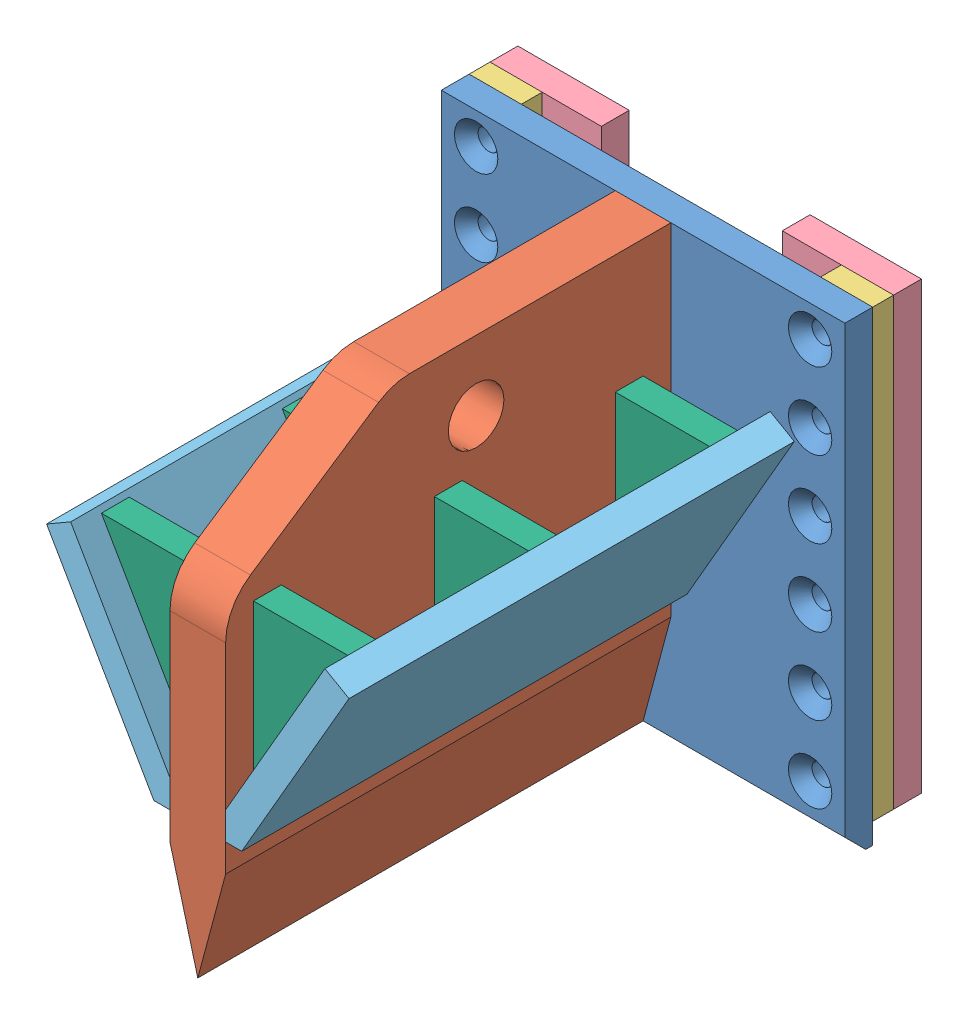
SolidWorks assembly Wedge Mk2 Assb, configuration Default. Lengths in mm.
Overall size (184.15 212.72 238.12).
14 component instances, 6 part files, 48 mates.
Components (placement in the parent):
- Wedge Mk2 Base-1: Wedge Mk2 Base [Default] at (37.464 81.8685 125.6409) size (184.15 212.72 12.7)
- Wedge Mk2-1: Wedge Mk2 [Default] at (37.464 -14.969 233.5909) size (25.4 203.2 203.2)
- Wedge Mk2 Spacer-1: Wedge Mk2 Spacer [Default] at (-42.7048 86.631 114.5284) x (-1 0 0) z (0 0 1) size (23.81 203.2 9.53)
- Wedge Mk2 Spacer-2: Wedge Mk2 Spacer [Default] at (117.6327 86.631 114.5284) size (23.81 203.2 9.53)
- Wedge Mk2 Guide-1: Wedge Mk2 Guide [Default] at (104.139 86.631 103.4159) x (-1 0 0) z (0 0 1) size (50.8 203.2 12.7)
- Wedge Mk2 Guide-2: Wedge Mk2 Guide [Default] at (-29.211 86.631 103.4159) size (50.8 203.2 12.7)
- Wedge Mk2 Spreader-1: Wedge Mk2 Spreader [Default] at (75.564 89.1221 233.5909) x (0.866025 -0.5 0) z (0 0 1) size (12.7 101.6 203.2)
- Wedge Mk2 Spreader-2: Wedge Mk2 Spreader [Default] at (-0.636 89.1221 233.5909) x (-0.866025 -0.5 0) z (0 0 -1) size (12.7 101.6 203.2)
- Wedge Mk2 Spreader Support-1: Wedge Mk2 Spreader Support [Default] at (24.764 134.028 151.0409) x (-1 0 0) z (0 0 -1) size (43.99 76.2 12.7)
- Wedge Mk2 Spreader Support-2: Wedge Mk2 Spreader Support [Default] at (24.764 134.028 233.5909) x (-1 0 0) z (0 0 -1) size (43.99 76.2 12.7)
- Wedge Mk2 Spreader Support-3: Wedge Mk2 Spreader Support [Default] at (24.764 134.028 316.1409) x (-1 0 0) z (0 0 -1) size (43.99 76.2 12.7)
- Wedge Mk2 Spreader Support-4: Wedge Mk2 Spreader Support [Default] at (50.164 134.028 316.1409) size (43.99 76.2 12.7)
- Wedge Mk2 Spreader Support-5: Wedge Mk2 Spreader Support [Default] at (50.164 134.028 233.5909) size (43.99 76.2 12.7)
- Wedge Mk2 Spreader Support-6: Wedge Mk2 Spreader Support [Default] at (50.164 134.028 151.0409) size (43.99 76.2 12.7)
Mates (geometry in assembly coordinates):
- Coincident3: coincident aligned: line of Wedge Mk2 Base-1 through (37.464 188.231 131.9909) axis (0 -1 0); line of Wedge Mk2-1 through (37.464 188.231 131.9909) axis (0 -1 0)
- Coincident4: coincident aligned: line of Wedge Mk2 Base-1 through (129.539 188.231 131.9909) axis (-1 0 0); line of Wedge Mk2-1 through (50.164 188.231 131.9909) axis (-1 0 0)
- Concentric1: concentric aligned: cylinder of Wedge Mk2 Base-1 through (113.664 173.9435 131.9909) axis (0 0 1) radius 4.9022; cylinder of Wedge Mk2 Spacer-2 through (113.664 173.9435 119.2909) axis (0 0 1) radius 4.7625
- Concentric2: concentric aligned: cylinder of Wedge Mk2 Base-1 through (113.664 139.0185 131.9909) axis (0 0 1) radius 4.9022; cylinder of Wedge Mk2 Spacer-2 through (113.664 139.0185 119.2909) axis (0 0 1) radius 4.7625
- Concentric3: concentric aligned: cylinder of Wedge Mk2 Base-1 through (113.664 104.0935 131.9909) axis (0 0 1) radius 4.9022; cylinder of Wedge Mk2 Spacer-2 through (113.664 104.0935 119.2909) axis (0 0 1) radius 4.7625
- Concentric4: concentric aligned: cylinder of Wedge Mk2 Base-1 through (113.664 69.1685 131.9909) axis (0 0 1) radius 4.9022; cylinder of Wedge Mk2 Spacer-2 through (113.664 69.1685 119.2909) axis (0 0 1) radius 4.7625
- Concentric5: concentric aligned: cylinder of Wedge Mk2 Base-1 through (113.664 34.2435 131.9909) axis (0 0 1) radius 4.9022; cylinder of Wedge Mk2 Spacer-2 through (113.664 34.2435 119.2909) axis (0 0 1) radius 4.7625
- Concentric6: concentric aligned: cylinder of Wedge Mk2 Base-1 through (113.664 -0.6815 131.9909) axis (0 0 1) radius 4.9022; cylinder of Wedge Mk2 Spacer-2 through (113.664 -0.6815 119.2909) axis (0 0 1) radius 4.7625
- Coincident17: coincident anti-aligned: plane of Wedge Mk2 Base-1 through (37.464 81.8685 119.2909) normal (0 0 -1); plane of Wedge Mk2 Spacer-2 through (117.6327 86.631 119.2909) normal (0 0 1)
- Concentric7: concentric aligned: cylinder of Wedge Mk2 Base-1 through (-38.736 173.9435 131.9909) axis (0 0 1) radius 4.9022; cylinder of Wedge Mk2 Spacer-1 through (-38.736 173.9435 119.2909) axis (0 0 1) radius 4.7625
- Concentric8: concentric aligned: cylinder of Wedge Mk2 Base-1 through (-38.736 139.0185 131.9909) axis (0 0 1) radius 4.9022; cylinder of Wedge Mk2 Spacer-1 through (-38.736 139.0185 119.2909) axis (0 0 1) radius 4.7625
- Concentric9: concentric aligned: cylinder of Wedge Mk2 Base-1 through (-38.736 104.0935 131.9909) axis (0 0 1) radius 4.9022; cylinder of Wedge Mk2 Spacer-1 through (-38.736 104.0935 119.2909) axis (0 0 1) radius 4.7625
- Concentric10: concentric aligned: cylinder of Wedge Mk2 Base-1 through (-38.736 69.1685 131.9909) axis (0 0 1) radius 4.9022; cylinder of Wedge Mk2 Spacer-1 through (-38.736 69.1685 119.2909) axis (0 0 1) radius 4.7625
- Concentric11: concentric aligned: cylinder of Wedge Mk2 Base-1 through (-38.736 34.2435 131.9909) axis (0 0 1) radius 4.9022; cylinder of Wedge Mk2 Spacer-1 through (-38.736 34.2435 119.2909) axis (0 0 1) radius 4.7625
- Concentric12: concentric aligned: cylinder of Wedge Mk2 Base-1 through (-38.736 -0.6815 131.9909) axis (0 0 1) radius 4.9022; cylinder of Wedge Mk2 Spacer-1 through (-38.736 -0.6815 119.2909) axis (0 0 1) radius 4.7625
- Coincident18: coincident anti-aligned: plane of Wedge Mk2 Base-1 through (37.464 81.8685 119.2909) normal (0 0 -1); plane of Wedge Mk2 Spacer-1 through (-42.7048 86.631 119.2909) normal (0 0 1)
- Concentric14: concentric aligned: cylinder of Wedge Mk2 Spacer-2 through (113.664 173.9435 119.2909) axis (0 0 1) radius 4.7625; cylinder of Wedge Mk2 Guide-1 through (113.664 173.9435 109.7659) axis (0 0 1) radius 4.7625
- Concentric15: concentric aligned: cylinder of Wedge Mk2 Spacer-2 through (113.664 139.0185 119.2909) axis (0 0 1) radius 4.7625; cylinder of Wedge Mk2 Guide-1 through (113.664 139.0185 109.7659) axis (0 0 1) radius 4.7625
- Concentric16: concentric aligned: cylinder of Wedge Mk2 Spacer-2 through (113.664 104.0935 119.2909) axis (0 0 1) radius 4.7625; cylinder of Wedge Mk2 Guide-1 through (113.664 104.0935 109.7659) axis (0 0 1) radius 4.7625
- Concentric17: concentric aligned: cylinder of Wedge Mk2 Spacer-2 through (113.664 69.1685 119.2909) axis (0 0 1) radius 4.7625; cylinder of Wedge Mk2 Guide-1 through (113.664 69.1685 109.7659) axis (0 0 1) radius 4.7625
- Concentric18: concentric aligned: cylinder of Wedge Mk2 Spacer-2 through (113.664 34.2435 119.2909) axis (0 0 1) radius 4.7625; cylinder of Wedge Mk2 Guide-1 through (113.664 34.2435 109.7659) axis (0 0 1) radius 4.7625
- Concentric19: concentric aligned: cylinder of Wedge Mk2 Spacer-2 through (113.664 -0.6815 119.2909) axis (0 0 1) radius 4.7625; cylinder of Wedge Mk2 Guide-1 through (113.664 -0.6815 109.7659) axis (0 0 1) radius 4.7625
- Coincident19: coincident anti-aligned: plane of Wedge Mk2 Spacer-2 through (117.6327 86.631 109.7659) normal (0 0 -1); plane of Wedge Mk2 Guide-1 through (104.139 86.631 109.7659) normal (0 0 1)
- Concentric20: concentric aligned: cylinder of Wedge Mk2 Spacer-1 through (-38.736 173.9435 119.2909) axis (0 0 1) radius 4.7625; cylinder of Wedge Mk2 Guide-2 through (-38.736 173.9435 109.7659) axis (0 0 1) radius 4.7625
- Concentric21: concentric aligned: cylinder of Wedge Mk2 Spacer-1 through (-38.736 139.0185 119.2909) axis (0 0 1) radius 4.7625; cylinder of Wedge Mk2 Guide-2 through (-38.736 139.0185 109.7659) axis (0 0 1) radius 4.7625
- Concentric22: concentric aligned: cylinder of Wedge Mk2 Spacer-1 through (-38.736 104.0935 119.2909) axis (0 0 1) radius 4.7625; cylinder of Wedge Mk2 Guide-2 through (-38.736 104.0935 109.7659) axis (0 0 1) radius 4.7625
- Concentric23: concentric aligned: cylinder of Wedge Mk2 Spacer-1 through (-38.736 69.1685 119.2909) axis (0 0 1) radius 4.7625; cylinder of Wedge Mk2 Guide-2 through (-38.736 69.1685 109.7659) axis (0 0 1) radius 4.7625
- Concentric24: concentric aligned: cylinder of Wedge Mk2 Spacer-1 through (-38.736 34.2435 119.2909) axis (0 0 1) radius 4.7625; cylinder of Wedge Mk2 Guide-2 through (-38.736 34.2435 109.7659) axis (0 0 1) radius 4.7625
- Concentric25: concentric aligned: cylinder of Wedge Mk2 Spacer-1 through (-38.736 -0.6815 119.2909) axis (0 0 1) radius 4.7625; cylinder of Wedge Mk2 Guide-2 through (-38.736 -0.6815 109.7659) axis (0 0 1) radius 4.7625
- Coincident20: coincident anti-aligned: plane of Wedge Mk2 Spacer-1 through (-42.7048 86.631 109.7659) normal (0 0 -1); plane of Wedge Mk2 Guide-2 through (-29.211 86.631 109.7659) normal (0 0 1)
- Coincident21: coincident anti-aligned: line of Wedge Mk2-1 through (50.164 57.828 316.1409) axis (0 1 0); line of Wedge Mk2 Spreader Support-4 through (50.164 134.028 316.1409) axis (0 -1 0)
- Coincident22: coincident aligned: line of Wedge Mk2-1 through (50.164 57.828 335.1909) axis (0 0 -1); line of Wedge Mk2 Spreader Support-4 through (50.164 57.828 322.4909) axis (0 0 -1)
- Coincident23: coincident anti-aligned: line of Wedge Mk2-1 through (50.164 57.828 233.5909) axis (0 1 0); line of Wedge Mk2 Spreader Support-5 through (50.164 134.028 233.5909) axis (0 -1 0)
- Coincident24: coincident aligned: line of Wedge Mk2-1 through (50.164 57.828 335.1909) axis (0 0 -1); line of Wedge Mk2 Spreader Support-5 through (50.164 57.828 239.9409) axis (0 0 -1)
- Coincident25: coincident aligned: line of Wedge Mk2-1 through (50.164 57.828 335.1909) axis (0 0 -1); line of Wedge Mk2 Spreader Support-6 through (50.164 57.828 157.3909) axis (0 0 -1)
- Coincident26: coincident anti-aligned: line of Wedge Mk2-1 through (50.164 57.828 151.0409) axis (0 1 0); line of Wedge Mk2 Spreader Support-6 through (50.164 134.028 151.0409) axis (0 -1 0)
- Coincident27: coincident anti-aligned: line of Wedge Mk2-1 through (24.764 57.828 316.1409) axis (0 1 0); line of Wedge Mk2 Spreader Support-3 through (24.764 134.028 316.1409) axis (0 -1 0)
- Coincident28: coincident aligned: line of Wedge Mk2-1 through (24.764 57.828 131.9909) axis (0 0 1); line of Wedge Mk2 Spreader Support-3 through (24.764 57.828 309.7909) axis (0 0 1)
- Coincident29: coincident aligned: line of Wedge Mk2-1 through (24.764 57.828 131.9909) axis (0 0 1); line of Wedge Mk2 Spreader Support-2 through (24.764 57.828 227.2409) axis (0 0 1)
- Coincident30: coincident anti-aligned: line of Wedge Mk2-1 through (24.764 57.828 233.5909) axis (0 1 0); line of Wedge Mk2 Spreader Support-2 through (24.764 134.028 233.5909) axis (0 -1 0)
- Coincident31: coincident anti-aligned: line of Wedge Mk2-1 through (24.764 57.828 151.0409) axis (0 1 0); line of Wedge Mk2 Spreader Support-1 through (24.764 134.028 151.0409) axis (0 -1 0)
- Coincident32: coincident aligned: line of Wedge Mk2-1 through (24.764 57.828 131.9909) axis (0 0 1); line of Wedge Mk2 Spreader Support-1 through (24.764 57.828 144.6909) axis (0 0 1)
- Coincident34: coincident anti-aligned: plane of Wedge Mk2 Spreader-2 through (4.8632 92.2971 233.5909) normal (0.866025 0.5 0); plane of Wedge Mk2 Spreader Support-2 through (-19.2301 134.028 227.2409) normal (-0.866025 -0.5 0)
- Coincident35: coincident aligned: plane of Wedge Mk2-1 through (37.464 -14.969 335.1909) normal (0 0 1); plane of Wedge Mk2 Spreader-2 through (-31.5353 129.9412 335.1909) normal (0 0 1)
- Coincident37: coincident anti-aligned: plane of Wedge Mk2 Spreader-1 through (70.0647 92.2971 233.5909) normal (-0.866025 0.5 0); plane of Wedge Mk2 Spreader Support-5 through (94.1581 134.028 239.9409) normal (0.866025 -0.5 0)
- Coincident38: coincident aligned: plane of Wedge Mk2-1 through (37.464 -14.969 335.1909) normal (0 0 1); plane of Wedge Mk2 Spreader-1 through (106.4632 129.9412 335.1909) normal (0 0 1)
- Coincident39: coincident anti-aligned: line of Wedge Mk2 Spreader-1 through (50.164 57.828 131.9909) axis (0 0 1); line of Wedge Mk2 Spreader Support-5 through (50.164 57.828 239.9409) axis (0 0 -1)
- Coincident40: coincident anti-aligned: line of Wedge Mk2 Spreader-2 through (24.764 57.828 335.1909) axis (0 0 -1); line of Wedge Mk2 Spreader Support-2 through (24.764 57.828 227.2409) axis (0 0 1)
